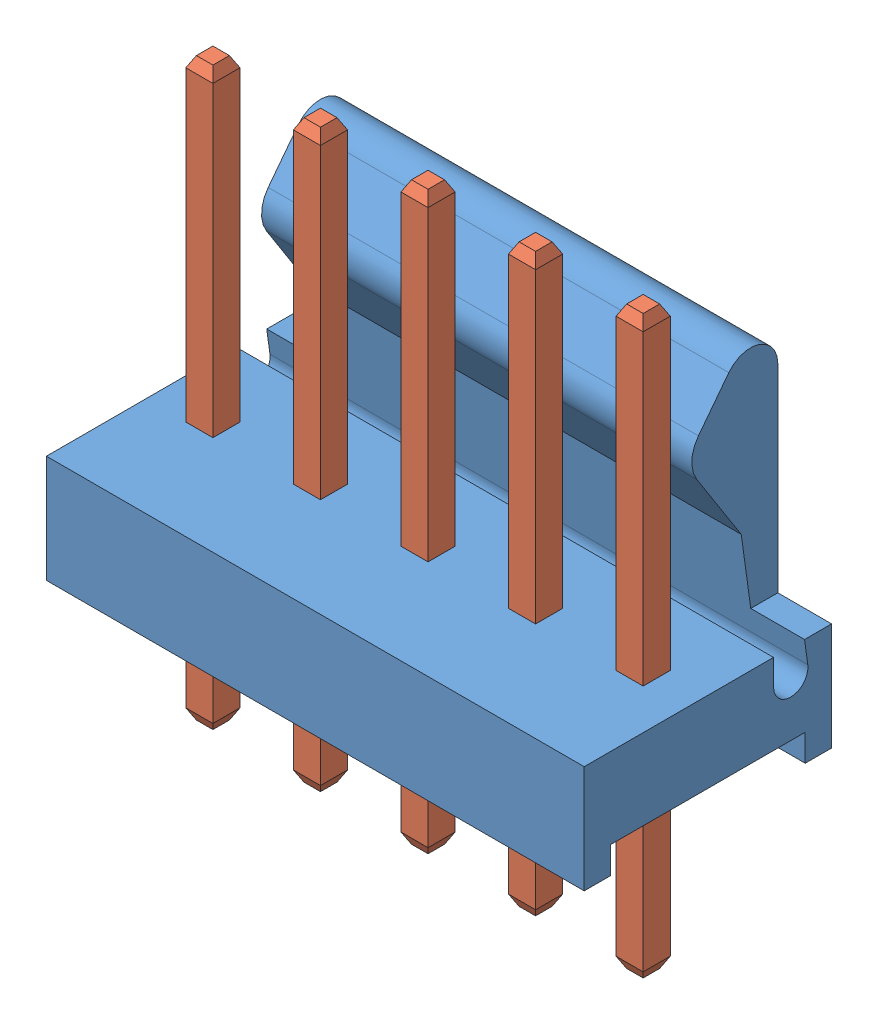
SolidWorks assembly 640456-5, configuration Default. Lengths in mm.
Overall size (12.7 13.59 5.84).
6 component instances, 2 part files, 15 mates.
Components (placement in the parent):
- 640456-5_body-1: 640456-5_body [Default] at (1.7763 -1.0989 -0.1908) size (12.7 7.87 5.84)
- 640456-5_pin-1: 640456-5_pin [Default] at (1.7738 -4.6539 2.9867) size (0.64 13.59 0.64)
- 640456-5_pin-2: 640456-5_pin [Default] at (4.3138 -4.6539 2.9867) size (0.64 13.59 0.64)
- 640456-5_pin-3: 640456-5_pin [Default] at (-0.7662 -4.6539 2.9867) size (0.64 13.59 0.64)
- 640456-5_pin-4: 640456-5_pin [Default] at (-3.3062 -4.6539 2.9867) size (0.64 13.59 0.64)
- 640456-5_pin-5: 640456-5_pin [Default] at (6.8538 -4.6539 2.9867) size (0.64 13.59 0.64)
Mates (geometry in assembly coordinates):
- Coincident1: coincident aligned: plane of 640456-5_pin-2 through (4.6338 -4.6539 3.3067) normal (0 -1 0); plane of 640456-5_pin-5 through (7.1738 -4.6539 3.3067) normal (0 -1 0)
- Coincident2: coincident aligned: plane of 640456-5_pin-1 through (2.0938 -4.6539 3.3067) normal (0 -1 0); plane of 640456-5_pin-2 through (4.6338 -4.6539 3.3067) normal (0 -1 0)
- Coincident3: coincident aligned: plane of 640456-5_pin-1 through (2.0938 -4.6539 3.3067) normal (0 -1 0); plane of 640456-5_pin-3 through (-0.4462 -4.6539 3.3067) normal (0 -1 0)
- Coincident4: coincident aligned: plane of 640456-5_pin-3 through (-0.4462 -4.6539 3.3067) normal (0 -1 0); plane of 640456-5_pin-4 through (-2.9862 -4.6539 3.3067) normal (0 -1 0)
- Coincident5: coincident aligned: plane of 640456-5_pin-3 through (-1.0862 8.9361 3.3067) normal (0 0 1); plane of 640456-5_pin-4 through (-3.6262 8.9361 3.3067) normal (0 0 1)
- Coincident6: coincident aligned: plane of 640456-5_pin-1 through (1.4538 8.9361 3.3067) normal (0 0 1); plane of 640456-5_pin-3 through (-1.0862 8.9361 3.3067) normal (0 0 1)
- Coincident7: coincident aligned: plane of 640456-5_pin-1 through (1.4538 8.9361 3.3067) normal (0 0 1); plane of 640456-5_pin-2 through (3.9938 8.9361 3.3067) normal (0 0 1)
- Coincident8: coincident aligned: plane of 640456-5_pin-2 through (3.9938 8.9361 3.3067) normal (0 0 1); plane of 640456-5_pin-5 through (6.5338 8.9361 3.3067) normal (0 0 1)
- Distance1: distance = 4.19 mm aligned: plane of 640456-5_pin-5 through (7.1738 -4.6539 3.3067) normal (0 -1 0); plane of 640456-5_body-1 through (-4.5737 -0.4639 5.0289) normal (0 -1 0)
- Coincident9: coincident anti-aligned: plane of 640456-5_body-1 through (7.1738 -4.6549 3.3017) normal (-1 0 0); plane of 640456-5_pin-5 through (7.1738 8.9361 2.6667) normal (1 0 0)
- Coincident10: coincident anti-aligned: plane of 640456-5_body-1 through (4.6338 -4.6549 3.3017) normal (-1 0 0); plane of 640456-5_pin-2 through (4.6338 8.9361 2.6667) normal (1 0 0)
- Coincident11: coincident anti-aligned: plane of 640456-5_body-1 through (2.0938 -4.6549 3.3017) normal (-1 0 0); plane of 640456-5_pin-1 through (2.0938 8.9361 2.6667) normal (1 0 0)
- Coincident12: coincident anti-aligned: plane of 640456-5_body-1 through (-0.4462 -4.6549 3.3017) normal (-1 0 0); plane of 640456-5_pin-3 through (-0.4462 8.9361 2.6667) normal (1 0 0)
- Coincident13: coincident anti-aligned: plane of 640456-5_body-1 through (-2.9862 -4.6549 3.3017) normal (-1 0 0); plane of 640456-5_pin-4 through (-2.9862 8.9361 2.6667) normal (1 0 0)
- Coincident14: coincident anti-aligned: plane of 640456-5_body-1 through (-2.9862 -4.6549 2.6667) normal (0 0 1); plane of 640456-5_pin-1 through (1.4538 8.9361 2.6667) normal (0 0 -1); sketch_entity of 640456-5_pin-1
